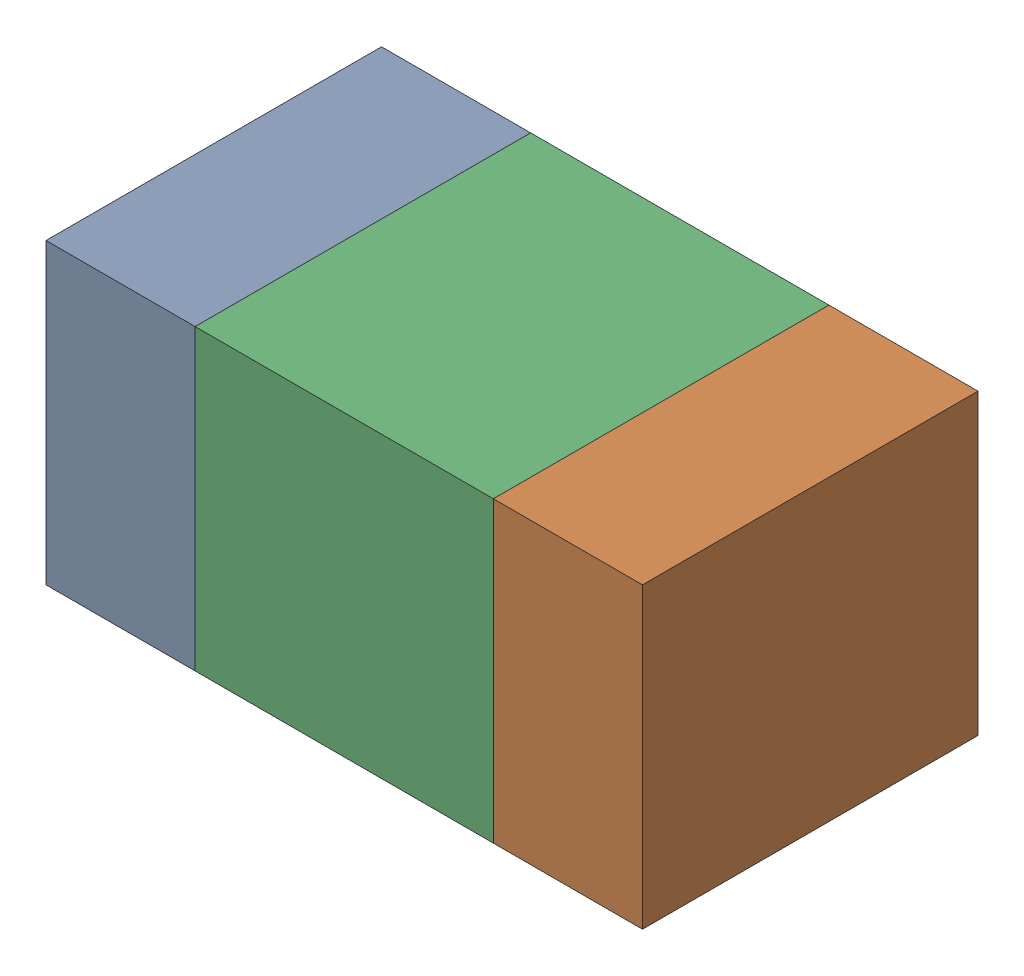
SolidWorks assembly C11, configuration ﾃﾞﾌｫﾙﾄ. Lengths in mm.
Overall size (1.6 0.8 0.9).
6 component instances, 2 part files, 0 mates.
Components (placement in the parent):
- 689259744-1: 689259744 [ﾃﾞﾌｫﾙﾄ] at (66.9001 53.5001 0) size (0.4 0.8 0.9)
  - Extruded_4-1: Extruded_4 [ﾃﾞﾌｫﾙﾄ] at origin size (0.4 0.8 0.9)
- 689259744-2: 689259744 [ﾃﾞﾌｫﾙﾄ] at (68.1001 53.5001 0) size (0.4 0.8 0.9)
  - Extruded_4-1: Extruded_4 [ﾃﾞﾌｫﾙﾄ] at origin size (0.4 0.8 0.9)
- 689259608-1: 689259608 [ﾃﾞﾌｫﾙﾄ] at (67.5 53.5001 0) size (0.8 0.8 0.9)
  - Extruded_3-1: Extruded_3 [ﾃﾞﾌｫﾙﾄ] at origin size (0.8 0.8 0.9)
